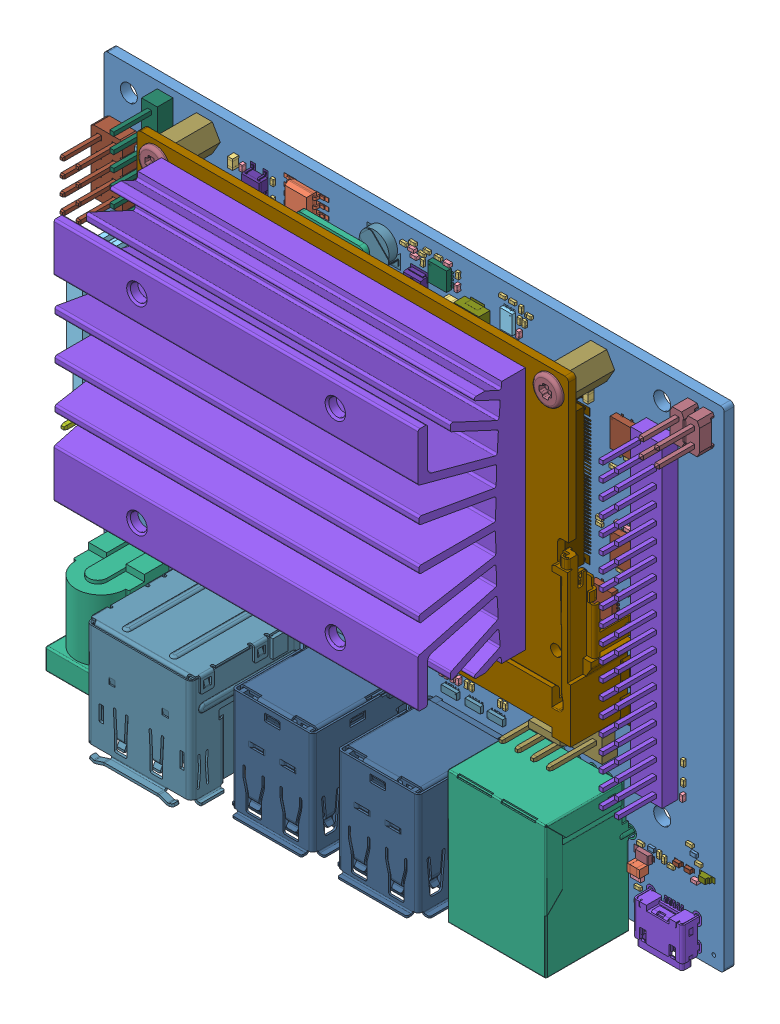
SolidWorks assembly Jetson nano 4GB For New, configuration Default. Lengths in mm.
Overall size (100 81.03 30.51).
388 component instances, 68 part files, 0 mates.
Components (placement in the parent):
- 142-13449-1000-A02_ASM-1: 142-13449-1000-A02_ASM [142-13449-1000-A02_ASM] at origin size (100 81.03 23.18)
  - 142-13449-1000-A02-1: 142-13449-1000-A02 [142-13449-1000-A02] at origin size (100 79 1.57)
  - 315-1109-000_1-1: 315-1109-000_1 [315-1109-000_1] at (5.6 4.9 1.575) x (-1 0 0) z (0 0 1) size (4.5 3.5 0.8)
  - 0402_H040-1: 0402_H040 [0402_H040] at (8 -0.825 1.575) size (1 0.5 0.4)
  - 0402_H060-1: 0402_H060 [0402_H060] at (1 5 1.575) x (0 -1 0) z (0 0 1) size (1 0.5 0.6)
  - 0402_H040-2: 0402_H040 [0402_H040] at (9.9 -0.3 1.575) size (1 0.5 0.4)
  - 0402_H040-3: 0402_H040 [0402_H040] at (8.296 51.194 1.575) x (-1 0 0) z (0 0 1) size (1 0.5 0.4)
  - 0402_H040-4: 0402_H040 [0402_H040] at (76.2 36.9 1.575) x (-1 0 0) z (0 0 1) size (1 0.5 0.4)
  - 0402_H040-5: 0402_H040 [0402_H040] at (37.8 2.87 1.575) x (0 -1 0) z (0 0 1) size (1 0.5 0.4)
  - 0402_H040-6: 0402_H040 [0402_H040] at (38.6 2.87 1.575) x (0 -1 0) z (0 0 1) size (1 0.5 0.4)
  - 0402_H060-2: 0402_H060 [0402_H060] at (14.2 7.7 1.575) x (0 -1 0) z (0 0 1) size (1 0.5 0.6)
  - 0402_H040-7: 0402_H040 [0402_H040] at (64 27.5 1.575) x (-1 0 0) z (0 0 1) size (1 0.5 0.4)
  - 0402_H060-3: 0402_H060 [0402_H060] at (18.6 43.15 1.575) x (-1 0 0) z (0 0 1) size (1 0.5 0.6)
  - 0402_H060-4: 0402_H060 [0402_H060] at (65.5 52.8 1.575) x (0 1 0) z (0 0 1) size (1 0.5 0.6)
  - 0402_H060-5: 0402_H060 [0402_H060] at (64 28.4 1.575) x (-1 0 0) z (0 0 1) size (1 0.5 0.6)
  - 0402_H040-8: 0402_H040 [0402_H040] at (60.95 25.85 1.575) size (1 0.5 0.4)
  - 0402_H060-6: 0402_H060 [0402_H060] at (17.3 7.7 1.575) x (0 -1 0) z (0 0 1) size (1 0.5 0.6)
  - 0402_H060-7: 0402_H060 [0402_H060] at (18.6 7.7 1.575) x (0 -1 0) z (0 0 1) size (1 0.5 0.6)
  - 0402_H060-8: 0402_H060 [0402_H060] at (12.9 7.7 1.575) x (0 -1 0) z (0 0 1) size (1 0.5 0.6)
  - 0402_H060-9: 0402_H060 [0402_H060] at (80.9 37.7 1.575) x (-1 0 0) z (0 0 1) size (1 0.5 0.6)
  - 0402_H040-9: 0402_H040 [0402_H040] at (79.5 31.3 1.575) size (1 0.5 0.4)
  - 0402_H040-10: 0402_H040 [0402_H040] at (81 31.3 1.575) x (-1 0 0) z (0 0 1) size (1 0.5 0.4)
  - 0402_H060-10: 0402_H060 [0402_H060] at (79.3 37.7 1.575) size (1 0.5 0.6)
  - 0402_H060-11: 0402_H060 [0402_H060] at (74.8 4.05 1.575) x (-1 0 0) z (0 0 1) size (1 0.5 0.6)
  - 0402_H040-11: 0402_H040 [0402_H040] at (65.675 6.15 1.575) x (0 -1 0) z (0 0 1) size (1 0.5 0.4)
  - 0402_H060-12: 0402_H060 [0402_H060] at (67.7 6.85 1.575) x (0 1 0) z (0 0 1) size (1 0.5 0.6)
  - 0402_H040-12: 0402_H040 [0402_H040] at (64.475 5.8 1.575) x (-1 0 0) z (0 0 1) size (1 0.5 0.4)
  - 0402_H040-13: 0402_H040 [0402_H040] at (67.725 5.325 1.575) x (0 1 0) z (0 0 1) size (1 0.5 0.4)
  - 0402_H060-13: 0402_H060 [0402_H060] at (46.1 59.45 1.575) size (1 0.5 0.6)
  - 0402_H040-14: 0402_H040 [0402_H040] at (44.65 59.45 1.575) size (1 0.5 0.4)
  - 0402_H040-15: 0402_H040 [0402_H040] at (46.1 60.25 1.575) size (1 0.5 0.4)
  - 0402_H060-14: 0402_H060 [0402_H060] at (53.35 57.7 1.575) x (0 -1 0) z (0 0 1) size (1 0.5 0.6)
  - 0402_H040-16: 0402_H040 [0402_H040] at (47.6 59.45 1.575) size (1 0.5 0.4)
  - 0402_H040-17: 0402_H040 [0402_H040] at (48.4 60.25 1.575) size (1 0.5 0.4)
  - 0402_H040-18: 0402_H040 [0402_H040] at (47.7 58.325 1.575) x (0 1 0) z (0 0 1) size (1 0.5 0.4)
  - 0402_H060-15: 0402_H060 [0402_H060] at (46.5 58.65 1.575) x (-1 0 0) z (0 0 1) size (1 0.5 0.6)
  - 0402_H060-16: 0402_H060 [0402_H060] at (51.8 60.25 1.575) size (1 0.5 0.6)
  - 0402_H040-19: 0402_H040 [0402_H040] at (53.35 59.4 1.575) x (0 -1 0) z (0 0 1) size (1 0.5 0.4)
  - 0402_H040-20: 0402_H040 [0402_H040] at (50.2 60.25 1.575) x (-1 0 0) z (0 0 1) size (1 0.5 0.4)
  - 0402_H060-17: 0402_H060 [0402_H060] at (18.6 43.95 1.575) x (-1 0 0) z (0 0 1) size (1 0.5 0.6)
  - 0402_H060-18: 0402_H060 [0402_H060] at (52.75 2.9 1.575) x (0 -1 0) z (0 0 1) size (1 0.5 0.6)
  - 0402_H060-19: 0402_H060 [0402_H060] at (22.35 47.4 1.575) x (-1 0 0) z (0 0 1) size (1 0.5 0.6)
  - 0402_H060-20: 0402_H060 [0402_H060] at (20.55 47.4 1.575) x (-1 0 0) z (0 0 1) size (1 0.5 0.6)
  - 0402_H060-21: 0402_H060 [0402_H060] at (21.95 34.55 1.575) x (0 -1 0) z (0 0 1) size (1 0.5 0.6)
  - 0402_H060-22: 0402_H060 [0402_H060] at (21.05 34.55 1.575) x (0 -1 0) z (0 0 1) size (1 0.5 0.6)
  - 0402_H060-23: 0402_H060 [0402_H060] at (53.55 2.9 1.575) x (0 -1 0) z (0 0 1) size (1 0.5 0.6)
  - 0402_H060-24: 0402_H060 [0402_H060] at (25.4 54 1.575) x (-1 0 0) z (0 0 1) size (1 0.5 0.6)
  - 0402_H060-25: 0402_H060 [0402_H060] at (24 34.58 1.575) x (0 -1 0) z (0 0 1) size (1 0.5 0.6)
  - 0402_H040-21: 0402_H040 [0402_H040] at (55.6 2.95 1.575) x (0 -1 0) z (0 0 1) size (1 0.5 0.4)
  - 0402_H040-22: 0402_H040 [0402_H040] at (20.13 34.53 1.575) x (0 1 0) z (0 0 1) size (1 0.5 0.4)
  - 0402_H060-26: 0402_H060 [0402_H060] at (18.4 35.15 1.575) x (0 1 0) z (0 0 1) size (1 0.5 0.6)
  - 0402_H060-27: 0402_H060 [0402_H060] at (18.4 36.75 1.575) x (0 1 0) z (0 0 1) size (1 0.5 0.6)
  - 0402_H040-23: 0402_H040 [0402_H040] at (39.6 2.87 1.575) x (0 -1 0) z (0 0 1) size (1 0.5 0.4)
  - 0402_H040-24: 0402_H040 [0402_H040] at (40.4 2.87 1.575) x (0 -1 0) z (0 0 1) size (1 0.5 0.4)
  - 0402_H040-25: 0402_H040 [0402_H040] at (60.95 2.95 1.575) x (0 -1 0) z (0 0 1) size (1 0.5 0.4)
  - 0402_H040-26: 0402_H040 [0402_H040] at (60.15 2.95 1.575) x (0 -1 0) z (0 0 1) size (1 0.5 0.4)
  - 0402_H040-27: 0402_H040 [0402_H040] at (54.8 2.95 1.575) x (0 -1 0) z (0 0 1) size (1 0.5 0.4)
  - 0402_H040-28: 0402_H040 [0402_H040] at (31.6 54 1.575) size (1 0.5 0.4)
  - 0402_H040-29: 0402_H040 [0402_H040] at (27.4 54 1.575) size (1 0.5 0.4)
  - 0402_H040-30: 0402_H040 [0402_H040] at (29.6 54 1.575) x (-1 0 0) z (0 0 1) size (1 0.5 0.4)
  - 0402_H040-31: 0402_H040 [0402_H040] at (63.775 -14.475 1.575) size (1 0.5 0.4)
  - 0402_H040-32: 0402_H040 [0402_H040] at (63.775 -15.275 1.575) size (1 0.5 0.4)
  - 0402_H040-33: 0402_H040 [0402_H040] at (8.025 41.475 1.575) x (-1 0 0) z (0 0 1) size (1 0.5 0.4)
  - 0402_H060-28: 0402_H060 [0402_H060] at (63.95 1.25 1.575) x (0 1 0) z (0 0 1) size (1 0.5 0.6)
  - 0402_H060-29: 0402_H060 [0402_H060] at (2.95 54.05 1.575) x (0 1 0) z (0 0 1) size (1 0.5 0.6)
  - 0402_H040-34: 0402_H040 [0402_H040] at (92.2 -3.45 1.575) x (-1 0 0) z (0 0 1) size (1 0.5 0.4)
  - 0402_H060-30: 0402_H060 [0402_H060] at (32.85 7.7 1.575) x (0 -1 0) z (0 0 1) size (1 0.5 0.6)
  - 0402_H060-31: 0402_H060 [0402_H060] at (27.25 7.7 1.575) x (0 -1 0) z (0 0 1) size (1 0.5 0.6)
  - 0402_H060-32: 0402_H060 [0402_H060] at (31.25 7.7 1.575) x (0 -1 0) z (0 0 1) size (1 0.5 0.6)
  - 0402_H060-33: 0402_H060 [0402_H060] at (28.85 7.7 1.575) x (0 -1 0) z (0 0 1) size (1 0.5 0.6)
  - 0402_H060-34: 0402_H060 [0402_H060] at (32.05 7.7 1.575) x (0 -1 0) z (0 0 1) size (1 0.5 0.6)
  - 0402_H060-35: 0402_H060 [0402_H060] at (28.05 7.7 1.575) x (0 -1 0) z (0 0 1) size (1 0.5 0.6)
  - 0402_H060-36: 0402_H060 [0402_H060] at (30.45 7.7 1.575) x (0 -1 0) z (0 0 1) size (1 0.5 0.6)
  - 0402_H060-37: 0402_H060 [0402_H060] at (29.65 7.7 1.575) x (0 -1 0) z (0 0 1) size (1 0.5 0.6)
  - 0402_H060-38: 0402_H060 [0402_H060] at (24.65 6.41 1.575) x (0 -1 0) z (0 0 1) size (1 0.5 0.6)
  - 0402_H060-39: 0402_H060 [0402_H060] at (25.85 6.41 1.575) x (0 -1 0) z (0 0 1) size (1 0.5 0.6)
  - 0402_H060-40: 0402_H060 [0402_H060] at (4.2 36.5 1.575) x (0 1 0) z (0 0 1) size (1 0.5 0.6)
  - 0402_H060-41: 0402_H060 [0402_H060] at (89.7 4.7 1.575) x (0 -1 0) z (0 0 1) size (1 0.5 0.6)
  - 0402_H060-42: 0402_H060 [0402_H060] at (82.5 3.8 1.575) x (0 -1 0) z (0 0 1) size (1 0.5 0.6)
  - 0402_H060-43: 0402_H060 [0402_H060] at (12.65 49.7 1.575) size (1 0.5 0.6)
  - 0402_H060-44: 0402_H060 [0402_H060] at (11.2 50.15 1.575) x (0 -1 0) z (0 0 1) size (1 0.5 0.6)
  - 0402_H060-45: 0402_H060 [0402_H060] at (26.5 34.55 1.575) x (0 -1 0) z (0 0 1) size (1 0.5 0.6)
  - 0402_H060-46: 0402_H060 [0402_H060] at (29.9 34.5 1.575) x (0 -1 0) z (0 0 1) size (1 0.5 0.6)
  - 0402_H060-47: 0402_H060 [0402_H060] at (31.7 40.15 1.575) x (0 1 0) z (0 0 1) size (1 0.5 0.6)
  - 0402_H060-48: 0402_H060 [0402_H060] at (31.15 42.5 1.575) x (0 1 0) z (0 0 1) size (1 0.5 0.6)
  - 0402_H060-49: 0402_H060 [0402_H060] at (19.2 47.05 1.575) x (0 1 0) z (0 0 1) size (1 0.5 0.6)
  - 0402_H060-50: 0402_H060 [0402_H060] at (17.95 42 1.575) x (0 -1 0) z (0 0 1) size (1 0.5 0.6)
  - 0402_H060-51: 0402_H060 [0402_H060] at (27.3 48.25 1.575) x (0 1 0) z (0 0 1) size (1 0.5 0.6)
  - 0402_H060-52: 0402_H060 [0402_H060] at (31.7 37.85 1.575) x (0 -1 0) z (0 0 1) size (1 0.5 0.6)
  - 0402_H060-53: 0402_H060 [0402_H060] at (29.6 48.35 1.575) x (0 1 0) z (0 0 1) size (1 0.5 0.6)
  - 0402_H060-54: 0402_H060 [0402_H060] at (18.8 38.75 1.575) x (-1 0 0) z (0 0 1) size (1 0.5 0.6)
  - 0402_H060-55: 0402_H060 [0402_H060] at (18.7 57.2 1.575) x (0 -1 0) z (0 0 1) size (1 0.5 0.6)
  - 0402_H060-56: 0402_H060 [0402_H060] at (34.1 2.9 1.575) x (0 -1 0) z (0 0 1) size (1 0.5 0.6)
  - 0402_H060-57: 0402_H060 [0402_H060] at (35.8 2.9 1.575) x (0 -1 0) z (0 0 1) size (1 0.5 0.6)
  - 0402_H060-58: 0402_H060 [0402_H060] at (34.9 2.9 1.575) x (0 -1 0) z (0 0 1) size (1 0.5 0.6)
  - 0402_H060-59: 0402_H060 [0402_H060] at (36.6 2.9 1.575) x (0 -1 0) z (0 0 1) size (1 0.5 0.6)
  - 0402_H060-60: 0402_H060 [0402_H060] at (11.325 44.725 1.575) size (1 0.5 0.6)
  - 0402_H060-61: 0402_H060 [0402_H060] at (50.95 2.9 1.575) x (0 -1 0) z (0 0 1) size (1 0.5 0.6)
  - 0402_H060-62: 0402_H060 [0402_H060] at (51.75 2.9 1.575) x (0 -1 0) z (0 0 1) size (1 0.5 0.6)
  - 0402_H060-63: 0402_H060 [0402_H060] at (11.55 39.7 1.575) size (1 0.5 0.6)
  - 0402_H060-64: 0402_H060 [0402_H060] at (9.5 -8.5 1.575) x (-1 0 0) z (0 0 1) size (1 0.5 0.6)
  - 0402_H060-65: 0402_H060 [0402_H060] at (61.35 38.05 1.575) x (0 -1 0) z (0 0 1) size (1 0.5 0.6)
  - 0402_H060-66: 0402_H060 [0402_H060] at (60.55 38.05 1.575) x (0 -1 0) z (0 0 1) size (1 0.5 0.6)
  - 0402_H060-67: 0402_H060 [0402_H060] at (29.3 25.65 1.575) x (0 -1 0) z (0 0 1) size (1 0.5 0.6)
  - 0402_H060-68: 0402_H060 [0402_H060] at (63.3 56.2 1.575) x (0 1 0) z (0 0 1) size (1 0.5 0.6)
  - 0402_H060-69: 0402_H060 [0402_H060] at (20.5 54.2 1.575) size (1 0.5 0.6)
  - 0402_H060-70: 0402_H060 [0402_H060] at (60.1 32.15 1.575) x (0 1 0) z (0 0 1) size (1 0.5 0.6)
  - 0402_H060-71: 0402_H060 [0402_H060] at (60.9 32.15 1.575) x (0 1 0) z (0 0 1) size (1 0.5 0.6)
  - 0402_H060-72: 0402_H060 [0402_H060] at (18.6 44.85 1.575) size (1 0.5 0.6)
  - 0402_H060-73: 0402_H060 [0402_H060] at (18.6 45.65 1.575) size (1 0.5 0.6)
  - 0402_H060-74: 0402_H060 [0402_H060] at (18.1 27.25 1.575) size (1 0.5 0.6)
  - 0402_H060-75: 0402_H060 [0402_H060] at (15.1 7.7 1.575) x (0 -1 0) z (0 0 1) size (1 0.5 0.6)
  - 0402_H060-76: 0402_H060 [0402_H060] at (16.4 7.7 1.575) x (0 -1 0) z (0 0 1) size (1 0.5 0.6)
  - 0402_H060-77: 0402_H060 [0402_H060] at (20.8 7.7 1.575) x (0 -1 0) z (0 0 1) size (1 0.5 0.6)
  - 0402_H060-78: 0402_H060 [0402_H060] at (19.5 7.7 1.575) x (0 -1 0) z (0 0 1) size (1 0.5 0.6)
  - 0402_H060-79: 0402_H060 [0402_H060] at (21.9 2.8 1.575) size (1 0.5 0.6)
  - 0402_H060-80: 0402_H060 [0402_H060] at (12.75 29 1.575) size (1 0.5 0.6)
  - 0402_H060-81: 0402_H060 [0402_H060] at (10.225 5.1 1.575) size (1 0.5 0.6)
  - 0402_H060-82: 0402_H060 [0402_H060] at (22.8 27.65 1.575) x (0 1 0) z (0 0 1) size (1 0.5 0.6)
  - 0402_H060-83: 0402_H060 [0402_H060] at (18.85 25.15 1.575) x (0 -1 0) z (0 0 1) size (1 0.5 0.6)
  - 0402_H060-84: 0402_H060 [0402_H060] at (17.95 40.1 1.575) x (0 1 0) z (0 0 1) size (1 0.5 0.6)
  - 0402_H040-35: 0402_H040 [0402_H040] at (20.8 6.2 1.575) x (0 1 0) z (0 0 1) size (1 0.5 0.4)
  - 0402_H040-36: 0402_H040 [0402_H040] at (76 22.7 1.575) size (1 0.5 0.4)
  - 0402_H040-37: 0402_H040 [0402_H040] at (23.7 26.85 1.575) x (0 1 0) z (0 0 1) size (1 0.5 0.4)
  - 0402_H040-38: 0402_H040 [0402_H040] at (18 25.15 1.575) x (0 1 0) z (0 0 1) size (1 0.5 0.4)
  - 0402_H040-39: 0402_H040 [0402_H040] at (17.3 28.25 1.575) x (-1 0 0) z (0 0 1) size (1 0.5 0.4)
  - 0402_H040-40: 0402_H040 [0402_H040] at (13.15 4.2 1.575) x (0 -1 0) z (0 0 1) size (1 0.5 0.4)
  - 0402_H040-41: 0402_H040 [0402_H040] at (17.2 30.15 1.575) x (0 -1 0) z (0 0 1) size (1 0.5 0.4)
  - 0402_H040-42: 0402_H040 [0402_H040] at (14.2 6.2 1.575) x (0 1 0) z (0 0 1) size (1 0.5 0.4)
  - 0402_H040-43: 0402_H040 [0402_H040] at (12.9 6.2 1.575) x (0 1 0) z (0 0 1) size (1 0.5 0.4)
  - 0402_H040-44: 0402_H040 [0402_H040] at (15.1 6.2 1.575) x (0 1 0) z (0 0 1) size (1 0.5 0.4)
  - 0402_H040-45: 0402_H040 [0402_H040] at (16.4 6.2 1.575) x (0 1 0) z (0 0 1) size (1 0.5 0.4)
  - 0402_H040-46: 0402_H040 [0402_H040] at (19.5 6.2 1.575) x (0 1 0) z (0 0 1) size (1 0.5 0.4)
  - 0402_H040-47: 0402_H040 [0402_H040] at (17.3 6.2 1.575) x (0 1 0) z (0 0 1) size (1 0.5 0.4)
  - 0402_H040-48: 0402_H040 [0402_H040] at (18.6 6.2 1.575) x (0 1 0) z (0 0 1) size (1 0.5 0.4)
  - 0402_H040-49: 0402_H040 [0402_H040] at (24.2 24.55 1.575) x (0 1 0) z (0 0 1) size (1 0.5 0.4)
  - 0402_H040-50: 0402_H040 [0402_H040] at (23.5 54.9 1.575) x (0 1 0) z (0 0 1) size (1 0.5 0.4)
  - 0402_H040-51: 0402_H040 [0402_H040] at (13.2 39.75 1.575) x (-1 0 0) z (0 0 1) size (1 0.5 0.4)
  - 0402_H040-52: 0402_H040 [0402_H040] at (80.7 47.4 1.575) x (-1 0 0) z (0 0 1) size (1 0.5 0.4)
  - 0402_H040-53: 0402_H040 [0402_H040] at (77.5 22.7 1.575) x (-1 0 0) z (0 0 1) size (1 0.5 0.4)
  - 0402_H040-54: 0402_H040 [0402_H040] at (9.25 -12.75 1.575) x (-1 0 0) z (0 0 1) size (1 0.5 0.4)
  - 0402_H040-55: 0402_H040 [0402_H040] at (9.25 -11.95 1.575) x (-1 0 0) z (0 0 1) size (1 0.5 0.4)
  - 0402_H040-56: 0402_H040 [0402_H040] at (64.475 6.7 1.575) size (1 0.5 0.4)
  - 0402_H040-57: 0402_H040 [0402_H040] at (29.3 24 1.575) x (0 1 0) z (0 0 1) size (1 0.5 0.4)
  - 0402_H040-58: 0402_H040 [0402_H040] at (64.2 32.5 1.575) x (0 1 0) z (0 0 1) size (1 0.5 0.4)
  - 0402_H040-59: 0402_H040 [0402_H040] at (64.15 47.45 1.575) x (0 -1 0) z (0 0 1) size (1 0.5 0.4)
  - 0402_H040-60: 0402_H040 [0402_H040] at (64.2 31 1.575) x (0 -1 0) z (0 0 1) size (1 0.5 0.4)
  - 0402_H040-61: 0402_H040 [0402_H040] at (76.2 36.1 1.575) x (-1 0 0) z (0 0 1) size (1 0.5 0.4)
  - 0402_H040-62: 0402_H040 [0402_H040] at (78.4 45.15 1.575) size (1 0.5 0.4)
  - 0402_H040-63: 0402_H040 [0402_H040] at (81.7 38.6 1.575) size (1 0.5 0.4)
  - 0402_H040-64: 0402_H040 [0402_H040] at (81.7 39.4 1.575) size (1 0.5 0.4)
  - 0402_H040-65: 0402_H040 [0402_H040] at (59.35 51.825 1.575) size (1 0.5 0.4)
  - 0402_H040-66: 0402_H040 [0402_H040] at (60.825 51.825 1.575) x (-1 0 0) z (0 0 1) size (1 0.5 0.4)
  - 0402_H040-67: 0402_H040 [0402_H040] at (89.7 9.5 1.575) x (0 1 0) z (0 0 1) size (1 0.5 0.4)
  - 0402_H040-68: 0402_H040 [0402_H040] at (89.7 6.7 1.575) x (0 1 0) z (0 0 1) size (1 0.5 0.4)
  - 0402_H040-69: 0402_H040 [0402_H040] at (3.9 34.2 1.575) x (0 -1 0) z (0 0 1) size (1 0.5 0.4)
  - 0402_H040-70: 0402_H040 [0402_H040] at (5.1 35 1.575) x (0 1 0) z (0 0 1) size (1 0.5 0.4)
  - 0402_H040-71: 0402_H040 [0402_H040] at (32.85 5.81 1.575) x (0 -1 0) z (0 0 1) size (1 0.5 0.4)
  - 0402_H040-72: 0402_H040 [0402_H040] at (32.05 5.81 1.575) x (0 -1 0) z (0 0 1) size (1 0.5 0.4)
  - 0402_H040-73: 0402_H040 [0402_H040] at (27.25 5.81 1.575) x (0 -1 0) z (0 0 1) size (1 0.5 0.4)
  - 0402_H040-74: 0402_H040 [0402_H040] at (28.05 5.81 1.575) x (0 -1 0) z (0 0 1) size (1 0.5 0.4)
  - 0402_H040-75: 0402_H040 [0402_H040] at (31.25 5.81 1.575) x (0 -1 0) z (0 0 1) size (1 0.5 0.4)
  - 0402_H040-76: 0402_H040 [0402_H040] at (30.45 5.81 1.575) x (0 -1 0) z (0 0 1) size (1 0.5 0.4)
  - 0402_H040-77: 0402_H040 [0402_H040] at (28.85 5.81 1.575) x (0 -1 0) z (0 0 1) size (1 0.5 0.4)
  - 0402_H040-78: 0402_H040 [0402_H040] at (29.65 5.81 1.575) x (0 -1 0) z (0 0 1) size (1 0.5 0.4)
  - 0402_H040-79: 0402_H040 [0402_H040] at (13.5 52.9 1.575) x (-1 0 0) z (0 0 1) size (1 0.5 0.4)
  - 0402_H040-80: 0402_H040 [0402_H040] at (22.35 4 1.575) x (0 -1 0) z (0 0 1) size (1 0.5 0.4)
  - 0402_H040-81: 0402_H040 [0402_H040] at (21.55 4 1.575) x (0 1 0) z (0 0 1) size (1 0.5 0.4)
  - 0402_H040-82: 0402_H040 [0402_H040] at (25.85 4.9 1.575) x (0 -1 0) z (0 0 1) size (1 0.5 0.4)
  - 0402_H040-83: 0402_H040 [0402_H040] at (11.8 52.9 1.575) size (1 0.5 0.4)
  - 0402_H040-84: 0402_H040 [0402_H040] at (9.432 51.594 1.575) x (0 -1 0) z (0 0 1) size (1 0.5 0.4)
  - 0402_H040-85: 0402_H040 [0402_H040] at (8.975 50.3 1.575) size (1 0.5 0.4)
  - 0402_H040-86: 0402_H040 [0402_H040] at (82.8 -5.3 1.575) x (-1 0 0) z (0 0 1) size (1 0.5 0.4)
  - 0402_H040-87: 0402_H040 [0402_H040] at (82.4 -11.6 1.575) x (-1 0 0) z (0 0 1) size (1 0.5 0.4)
  - 0402_H040-88: 0402_H040 [0402_H040] at (22.8 26.05 1.575) x (0 1 0) z (0 0 1) size (1 0.5 0.4)
  - 0402_H040-89: 0402_H040 [0402_H040] at (20.8 28.25 1.575) size (1 0.5 0.4)
  - 0402_H040-90: 0402_H040 [0402_H040] at (20.8 24.65 1.575) x (-1 0 0) z (0 0 1) size (1 0.5 0.4)
  - 0402_H040-91: 0402_H040 [0402_H040] at (18.1 26.45 1.575) size (1 0.5 0.4)
  - 0402_H040-92: 0402_H040 [0402_H040] at (24.65 8.41 1.575) x (0 1 0) z (0 0 1) size (1 0.5 0.4)
  - 0402_H040-93: 0402_H040 [0402_H040] at (25.85 8.41 1.575) x (0 1 0) z (0 0 1) size (1 0.5 0.4)
  - 0402_H040-94: 0402_H040 [0402_H040] at (3.8 54.4 1.575) x (0 -1 0) z (0 0 1) size (1 0.5 0.4)
  - 0402_H040-95: 0402_H040 [0402_H040] at (2.45 44.45 1.575) x (0 -1 0) z (0 0 1) size (1 0.5 0.4)
  - 0402_H040-96: 0402_H040 [0402_H040] at (24.65 4.9 1.575) x (0 1 0) z (0 0 1) size (1 0.5 0.4)
  - 0402_H040-97: 0402_H040 [0402_H040] at (22.15 7.6 1.575) x (-1 0 0) z (0 0 1) size (1 0.5 0.4)
  - 0402_H040-98: 0402_H040 [0402_H040] at (79.2 47.4 1.575) size (1 0.5 0.4)
  - 0402_H040-99: 0402_H040 [0402_H040] at (19 28.25 1.575) size (1 0.5 0.4)
  - 0402_H040-100: 0402_H040 [0402_H040] at (9.65 9.7 1.575) x (0 -1 0) z (0 0 1) size (1 0.5 0.4)
  - 0402_H040-101: 0402_H040 [0402_H040] at (28.35 34.45 1.575) x (0 1 0) z (0 0 1) size (1 0.5 0.4)
  - 0402_H040-102: 0402_H040 [0402_H040] at (25.2 34.55 1.575) x (0 1 0) z (0 0 1) size (1 0.5 0.4)
  - 0402_H040-103: 0402_H040 [0402_H040] at (10.625 6.35 1.575) x (0 -1 0) z (0 0 1) size (1 0.5 0.4)
  - 0402_H040-104: 0402_H040 [0402_H040] at (9.825 6.35 1.575) x (0 1 0) z (0 0 1) size (1 0.5 0.4)
  - 0402_H040-105: 0402_H040 [0402_H040] at (4.775 42.975 1.575) x (0 1 0) z (0 0 1) size (1 0.5 0.4)
  - 0402_H040-106: 0402_H040 [0402_H040] at (19.8 32.9 1.575) x (-1 0 0) z (0 0 1) size (1 0.5 0.4)
  - 0402_H040-107: 0402_H040 [0402_H040] at (22.35 24.65 1.575) x (-1 0 0) z (0 0 1) size (1 0.5 0.4)
  - 0402_H040-108: 0402_H040 [0402_H040] at (62.4 54.7 1.575) size (1 0.5 0.4)
  - 0402_H040-109: 0402_H040 [0402_H040] at (62.2 60.05 1.575) x (-1 0 0) z (0 0 1) size (1 0.5 0.4)
  - 0402_H040-110: 0402_H040 [0402_H040] at (23.5 57.5 1.575) x (0 1 0) z (0 0 1) size (1 0.5 0.4)
  - 0402_H040-111: 0402_H040 [0402_H040] at (12.8 44.725 1.575) size (1 0.5 0.4)
  - 0402_H040-112: 0402_H040 [0402_H040] at (21.8 31.45 1.575) x (0 1 0) z (0 0 1) size (1 0.5 0.4)
  - 0402_H040-113: 0402_H040 [0402_H040] at (19.25 34.55 1.575) x (0 1 0) z (0 0 1) size (1 0.5 0.4)
  - 0402_H040-114: 0402_H040 [0402_H040] at (0.95 41.55 1.575) size (1 0.5 0.4)
  - 0402_H040-115: 0402_H040 [0402_H040] at (64.1 58 1.575) x (0 1 0) z (0 0 1) size (1 0.5 0.4)
  - 0402_H040-116: 0402_H040 [0402_H040] at (63.3 58 1.575) x (0 -1 0) z (0 0 1) size (1 0.5 0.4)
  - 0402_H040-117: 0402_H040 [0402_H040] at (63.55 59.7 1.575) x (0 -1 0) z (0 0 1) size (1 0.5 0.4)
  - 0402_H060-85: 0402_H060 [0402_H060] at (71.175 4 1.575) x (-1 0 0) z (0 0 1) size (1 0.5 0.6)
  - 0402_H040-118: 0402_H040 [0402_H040] at (86.6 -5.6 1.575) x (0 1 0) z (0 0 1) size (1 0.5 0.4)
  - 0402_H040-119: 0402_H040 [0402_H040] at (85.8 -5.3 1.575) x (0 1 0) z (0 0 1) size (1 0.5 0.4)
  - 0402_H040-120: 0402_H040 [0402_H040] at (10.25 51.6 1.575) x (0 1 0) z (0 0 1) size (1 0.5 0.4)
  - 0402_H040-121: 0402_H040 [0402_H040] at (80.5 28.55 1.575) size (1 0.5 0.4)
  - 0402_H040-122: 0402_H040 [0402_H040] at (13.95 4.2 1.575) x (0 -1 0) z (0 0 1) size (1 0.5 0.4)
  - 0402_H040-123: 0402_H040 [0402_H040] at (15.35 4.2 1.575) x (0 -1 0) z (0 0 1) size (1 0.5 0.4)
  - 0402_H040-124: 0402_H040 [0402_H040] at (16.15 4.2 1.575) x (0 -1 0) z (0 0 1) size (1 0.5 0.4)
  - 0402_H040-125: 0402_H040 [0402_H040] at (20.55 4.2 1.575) x (0 -1 0) z (0 0 1) size (1 0.5 0.4)
  - 0402_H040-126: 0402_H040 [0402_H040] at (19.75 4.2 1.575) x (0 -1 0) z (0 0 1) size (1 0.5 0.4)
  - 0402_H040-127: 0402_H040 [0402_H040] at (17.6 4.2 1.575) x (0 -1 0) z (0 0 1) size (1 0.5 0.4)
  - 0402_H040-128: 0402_H040 [0402_H040] at (18.4 4.2 1.575) x (0 -1 0) z (0 0 1) size (1 0.5 0.4)
  - 0402_H060-86: 0402_H060 [0402_H060] at (64.25 -13.325 1.575) x (0 -1 0) z (0 0 1) size (1 0.5 0.6)
  - 0402_H060-87: 0402_H060 [0402_H060] at (64.225 -11.825 1.575) x (0 1 0) z (0 0 1) size (1 0.5 0.6)
  - 0402_H040-129: 0402_H040 [0402_H040] at (63.8 -6.85 1.575) x (0 1 0) z (0 0 1) size (1 0.5 0.4)
  - 0402_H040-130: 0402_H040 [0402_H040] at (81.7 41.95 1.575) size (1 0.5 0.4)
  - 0402_H040-131: 0402_H040 [0402_H040] at (87.75 -6 1.575) x (-1 0 0) z (0 0 1) size (1 0.5 0.4)
  - 0402_H040-132: 0402_H040 [0402_H040] at (82.4 -13.6 1.575) x (-1 0 0) z (0 0 1) size (1 0.5 0.4)
  - 0402_H060-88: 0402_H060 [0402_H060] at (91.75 -5.95 1.575) size (1 0.5 0.6)
  - 0402_H040-133: 0402_H040 [0402_H040] at (3.65 49.25 1.575) x (0 -1 0) z (0 0 1) size (1 0.5 0.4)
  - 0402_H040-134: 0402_H040 [0402_H040] at (2.45 49.25 1.575) x (0 1 0) z (0 0 1) size (1 0.5 0.4)
  - 0402_H040-135: 0402_H040 [0402_H040] at (90.75 -1.45 1.575) x (-1 0 0) z (0 0 1) size (1 0.5 0.4)
  - 0402_H040-136: 0402_H040 [0402_H040] at (8.45 39.55 1.575) x (0 -1 0) z (0 0 1) size (1 0.5 0.4)
  - 0402_H060-89: 0402_H060 [0402_H060] at (8.85 -5.25 1.575) x (-1 0 0) z (0 0 1) size (1 0.5 0.6)
  - 0402_H040-137: 0402_H040 [0402_H040] at (18.6 32.55 1.575) x (0 1 0) z (0 0 1) size (1 0.5 0.4)
  - 0402_H060-90: 0402_H060 [0402_H060] at (4.5 44.45 1.575) x (0 1 0) z (0 0 1) size (1 0.5 0.6)
  - 0402_H040-138: 0402_H040 [0402_H040] at (8.35 2.75 1.575) size (1 0.5 0.4)
  - 0402_H040-139: 0402_H040 [0402_H040] at (9.4 1.95 1.575) size (1 0.5 0.4)
  - 0402_H040-140: 0402_H040 [0402_H040] at (8.2 1.55 1.575) x (0 1 0) z (0 0 1) size (1 0.5 0.4)
  - 0402_H060-91: 0402_H060 [0402_H060] at (8.5 3.875 1.575) x (0 -1 0) z (0 0 1) size (1 0.5 0.6)
  - 0402_H060-92: 0402_H060 [0402_H060] at (-0.8 41.5 1.575) x (-1 0 0) z (0 0 1) size (1 0.5 0.6)
  - 0402_H040-141: 0402_H040 [0402_H040] at (-1.35 7.75 1.575) size (1 0.5 0.4)
  - 0402_H040-142: 0402_H040 [0402_H040] at (8 0.425 1.575) size (1 0.5 0.4)
  - 0402_H040-143: 0402_H040 [0402_H040] at (67.9 4.025 1.575) x (-1 0 0) z (0 0 1) size (1 0.5 0.4)
  - 0402_H040-144: 0402_H040 [0402_H040] at (60.6 60.05 1.575) x (-1 0 0) z (0 0 1) size (1 0.5 0.4)
  - 0402_H040-145: 0402_H040 [0402_H040] at (72.85 4 1.575) x (-1 0 0) z (0 0 1) size (1 0.5 0.4)
  - 0402_H040-146: 0402_H040 [0402_H040] at (64.8 59.35 1.575) size (1 0.5 0.4)
  - 0402_H040-147: 0402_H040 [0402_H040] at (7.2 7.3 1.575) size (1 0.5 0.4)
  - 0402_H040-148: 0402_H040 [0402_H040] at (8.5 5.35 1.575) x (0 1 0) z (0 0 1) size (1 0.5 0.4)
  - 0402_H040-149: 0402_H040 [0402_H040] at (8.475 7.075 1.575) x (0 1 0) z (0 0 1) size (1 0.5 0.4)
  - VIRTUAL_SHORT-1: VIRTUAL_SHORT [VIRTUAL_SHORT] at (23.5 32.9 1.575) x (0 1 0) z (0 0 1) size (0.25 0.25 1)
  - VIRTUAL_SHORT-2: VIRTUAL_SHORT [VIRTUAL_SHORT] at (26.85 32.85 1.575) x (0 1 0) z (0 0 1) size (0.25 0.25 1)
  - VIRTUAL_SHORT-3: VIRTUAL_SHORT [VIRTUAL_SHORT] at (30.6 33.8 1.575) x (0 1 0) z (0 0 1) size (0.25 0.25 1)
  - VIRTUAL_SHORT-4: VIRTUAL_SHORT [VIRTUAL_SHORT] at (32.65 39.75 1.575) x (-1 0 0) z (0 0 1) size (0.25 0.25 1)
  - VIRTUAL_SHORT-5: VIRTUAL_SHORT [VIRTUAL_SHORT] at (31.85 42.1 1.575) x (-1 0 0) z (0 0 1) size (0.25 0.25 1)
  - VIRTUAL_SHORT-6: VIRTUAL_SHORT [VIRTUAL_SHORT] at (17.35 42.4 1.575) size (0.25 0.25 1)
  - VIRTUAL_SHORT-7: VIRTUAL_SHORT [VIRTUAL_SHORT] at (18.6 46.6 1.575) size (0.25 0.25 1)
  - VIRTUAL_SHORT-8: VIRTUAL_SHORT [VIRTUAL_SHORT] at (20.9 32.9 1.575) x (0 1 0) z (0 0 1) size (0.25 0.25 1)
  - VIRTUAL_SHORT-9: VIRTUAL_SHORT [VIRTUAL_SHORT] at (28.6 48.25 1.575) x (0 -1 0) z (0 0 1) size (0.25 0.25 1)
  - VIRTUAL_SHORT-10: VIRTUAL_SHORT [VIRTUAL_SHORT] at (27.1 49.35 1.575) x (0 -1 0) z (0 0 1) size (0.25 0.25 1)
  - VIRTUAL_SHORT-11: VIRTUAL_SHORT [VIRTUAL_SHORT] at (22.1 32.95 1.575) x (-1 0 0) z (0 0 1) size (0.25 0.25 1)
  - VIRTUAL_SHORT-12: VIRTUAL_SHORT [VIRTUAL_SHORT] at (32.65 38.25 1.575) x (-1 0 0) z (0 0 1) size (0.25 0.25 1)
  - VIRTUAL_SHORT-13: VIRTUAL_SHORT [VIRTUAL_SHORT] at (30.3 48 1.575) x (-1 0 0) z (0 0 1) size (0.25 0.25 1)
  - VIRTUAL_SHORT-14: VIRTUAL_SHORT [VIRTUAL_SHORT] at (17.15 38.95 1.575) size (0.25 0.25 1)
  - VIRTUAL_SHORT-15: VIRTUAL_SHORT [VIRTUAL_SHORT] at (17.15 39.7 1.575) size (0.25 0.25 1)
  - VIRTUAL_SHORT-16: VIRTUAL_SHORT [VIRTUAL_SHORT] at (76.175 4.1 1.575) x (-1 0 0) z (0 0 1) size (0.25 0.25 1)
  - 064-0377-000_2-1: 064-0377-000_2 [064-0377-000_2] at (2 -4.75 1.575) x (0 -1 0) z (0 0 1) size (14.63 10.08 14.5)
  - 074-0117-000_2-1: 074-0117-000_2 [074-0117-000_2] at (0.254 14.3 1.575) size (5.08 2.54 11.66)
  - 090-0096-000_1-1: 090-0096-000_1 [090-0096-000_1] at (3.45 44.4 1.575) x (0 -1 0) z (0 0 1) size (1.2 0.6 0.4)
  - 090-0309-000_1-1: 090-0309-000_1 [090-0309-000_1] at (-1.65 8.7 1.575) x (-1 0 0) z (0 0 1) size (1.2 0.6 0.4)
  - 115-1232-000_2-1: 115-1232-000_2 [115-1232-000_2] at (1.25 6.5 1.575) x (-1 0 0) z (0 0 1) size (0.9 0.9 0.33)
  - 074-0102-000_4-1: 074-0102-000_4 [074-0102-000_4] at (0.254 44.36 1.575) x (0 1 0) z (0 0 1) size (10.16 5.08 11.6)
  - 064-0400-000_1-1: 064-0400-000_1 [064-0400-000_1] at (73.75 7.77 1.575) size (10.16 5.8 13.5)
  - MEC_STANDOFF_PTH_620C380P-1: MEC_STANDOFF_PTH_620C380P [MEC_STANDOFF_PTH_620C380P] at (40.276 40.3 1.575) x (0 1 0) z (0 0 1) size (6.2 6.2 0.73)
  - 090-0231-000_1-1: 090-0231-000_1 [090-0231-000_1] at (35.3 0.7 1.575) x (-1 0 0) z (0 0 1) size (2.5 1.55 0.55)
  - 090-0231-000_1-2: 090-0231-000_1 [090-0231-000_1] at (52.25 0.7 1.575) x (-1 0 0) z (0 0 1) size (2.5 1.55 0.55)
  - 090-0231-000_1-3: 090-0231-000_1 [090-0231-000_1] at (56.05 0.7 1.575) size (2.5 1.55 0.55)
  - 090-0231-000_1-4: 090-0231-000_1 [090-0231-000_1] at (59.65 0.7 1.575) size (2.5 1.55 0.55)
  - 090-0231-000_1-5: 090-0231-000_1 [090-0231-000_1] at (39.1 0.7 1.575) size (2.5 1.55 0.55)
  - 090-0231-000_1-6: 090-0231-000_1 [090-0231-000_1] at (43.1 0.7 1.575) size (2.5 1.55 0.55)
  - 090-0231-000_1-7: 090-0231-000_1 [090-0231-000_1] at (14.6 1.8 1.575) size (2.5 1.55 0.55)
  - 090-0231-000_1-8: 090-0231-000_1 [090-0231-000_1] at (19.1 1.8 1.575) size (2.5 1.55 0.55)
  - 090-0231-000_1-9: 090-0231-000_1 [090-0231-000_1] at (22.5 1.4 1.575) size (2.5 1.55 0.55)
  - 090-0231-000_1-10: 090-0231-000_1 [090-0231-000_1] at (28.45 3.35 1.575) size (2.5 1.55 0.55)
  - 090-0231-000_1-11: 090-0231-000_1 [090-0231-000_1] at (31.65 3.35 1.575) size (2.5 1.55 0.55)
  - 074-0223-000_2-1: 074-0223-000_2 [074-0223-000_2] at (5.85 53.25 1.575) x (0 1 0) z (0 0 1) size (15.24 2.54 11.6)
  - 131-0832-000_2-1: 131-0832-000_2 [131-0832-000_2] at (56.3 54.7 1.575) x (0 -1 0) z (0 0 1) size (4.96 4.06 1.8)
  - 115-0836-000_1-1: 115-0836-000_1 [115-0836-000_1] at (21.1 56.6 1.575) size (2.9 3.58 1.45)
  - 115-0836-000_1-2: 115-0836-000_1 [115-0836-000_1] at (11.8 42.3 1.575) size (2.9 3.58 1.45)
  - 315-0620-000_1-1: 315-0620-000_1 [315-0620-000_1] at (72.1 53.4 1.575) x (0 -1 0) z (0 0 1) size (2.9 3.58 1.1)
  - 315-1062-000_1-1: 315-1062-000_1 [315-1062-000_1] at (26.8 25.15 1.575) x (0 -1 0) z (0 0 1) size (2.9 3.58 1.45)
  - 170-0285-000_1-1: 170-0285-000_1 [170-0285-000_1] at (28.72 57.28 1.575) x (0 1 0) z (0 0 1) size (4.9 7.21 1.75)
  - 115-0138-000_1-1: 115-0138-000_1 [115-0138-000_1] at (9.15 48.55 1.575) x (0 1 0) z (0 0 1) size (2 2.88 1.1)
  - 115-1821-000_1-1: 115-1821-000_1 [115-1821-000_1] at (3.3 40.8 1.575) x (-1 0 0) z (0 0 1) size (2 2.88 1.1)
  - 115-1821-000_1-2: 115-1821-000_1 [115-1821-000_1] at (6.25 39.55 1.575) x (0 -1 0) z (0 0 1) size (2 2.88 1.1)
  - 115-0742-000_2-1: 115-0742-000_2 [115-0742-000_2] at (3.05 46.85 1.575) size (2 2.88 1.1)
  - 115-0742-000_2-2: 115-0742-000_2 [115-0742-000_2] at (3.05 51.65 1.575) x (-1 0 0) z (0 0 1) size (2 2.88 1.1)
  - 115-1821-000_1-3: 115-1821-000_1 [115-1821-000_1] at (59.6 27.6 1.575) x (0 1 0) z (0 0 1) size (2 2.88 1.1)
  - 091-0022-000_1-1: 091-0022-000_1 [091-0022-000_1] at (-0.95 5.7 1.575) size (2 2.51 1.1)
  - 091-0023-000_1-1: 091-0023-000_1 [091-0023-000_1] at (15.25 29.9 1.575) x (0 -1 0) z (0 0 1) size (2 2.51 1.1)
  - 080-1368-000_1-1: 080-1368-000_1 [080-1368-000_1] at (88 -14.3 1.575) size (10.99 7.28 4.95)
  - 080-1656-000_3-1: 080-1656-000_3 [080-1656-000_3] at (44 16.6 1.575) x (-1 0 0) z (0 0 1) size (77.5 25.85 9.76)
  - 090-0243-000_1-1: 090-0243-000_1 [090-0243-000_1] at (8.5 -4.1 1.575) x (-1 0 0) z (0 0 1) size (1.41 0.61 0.45)
  - 090-0243-000_1-2: 090-0243-000_1 [090-0243-000_1] at (9.95 -3.7 1.575) x (0 1 0) z (0 0 1) size (1.41 0.61 0.45)
  - 090-0243-000_1-3: 090-0243-000_1 [090-0243-000_1] at (9.5 -10.95 1.575) x (-1 0 0) z (0 0 1) size (1.41 0.61 0.45)
  - 090-0243-000_1-4: 090-0243-000_1 [090-0243-000_1] at (9.8 -6.25 1.575) x (-1 0 0) z (0 0 1) size (1.41 0.61 0.45)
  - 090-0243-000_1-5: 090-0243-000_1 [090-0243-000_1] at (9.5 -9.5 1.575) x (-1 0 0) z (0 0 1) size (1.41 0.61 0.45)
  - 090-0172-000_1-1: 090-0172-000_1 [090-0172-000_1] at (90.6 -5 1.575) size (1.41 0.61 0.55)
  - 090-0172-000_1-2: 090-0172-000_1 [090-0172-000_1] at (88.8 -5 1.575) x (-1 0 0) z (0 0 1) size (1.41 0.61 0.55)
  - 115-2177-000_2-1: 115-2177-000_2 [115-2177-000_2] at (12.7 51.35 1.575) x (0 1 0) z (0 0 1) size (1.8 1.71 0.4)
  - 090-0233-000_1-1: 090-0233-000_1 [090-0233-000_1] at (83.5 -6.6 1.575) size (3.3 1.3 0.74)
  - 064-0374-000_2-1: 064-0374-000_2 [064-0374-000_2] at (19.75 -9.65 1.575) size (18.1 18.55 21.85)
  - 115-2628-000_3-1: 115-2628-000_3 [115-2628-000_3] at (25.2 41.2 1.575) size (9.5 9.5 0.9)
  - 092-0073-000_1-1: 092-0073-000_1 [092-0073-000_1] at (93.35 -4.75 1.575) x (-1 0 0) z (0 0 1) size (2.46 0.81 0.9)
  - IND_SMD_0402_H060-1: IND_SMD_0402_H060 [IND_SMD_0402_H060] at (12.85 29.9 1.575) x (-1 0 0) z (0 0 1) size (1 0.5 0.6)
  - 1206_H190-1: 1206_H190 [1206_H190] at (82 18.8 1.575) x (0 1 0) z (0 0 1) size (3.2 1.6 1.9)
  - 1206_H190-2: 1206_H190 [1206_H190] at (81.95 13.5 1.575) x (0 -1 0) z (0 0 1) size (3.2 1.6 1.9)
  - 300-0868-000_3-1: 300-0868-000_3 [300-0868-000_3] at (69.6 4 1.575) x (-1 0 0) z (0 0 1) size (1 0.6 0.4)
  - 300-0868-000_3-2: 300-0868-000_3 [300-0868-000_3] at (9.55 0.95 1.575) size (1 0.6 0.4)
  - 300-0868-000_3-3: 300-0868-000_3 [300-0868-000_3] at (19.6 31.45 1.575) x (0 -1 0) z (0 0 1) size (1 0.6 0.4)
  - 300-0868-000_3-4: 300-0868-000_3 [300-0868-000_3] at (91.45 -2.45 1.575) x (-1 0 0) z (0 0 1) size (1 0.6 0.4)
  - 300-0868-000_3-5: 300-0868-000_3 [300-0868-000_3] at (84.6 -5.1 1.575) size (1 0.6 0.4)
  - 300-0868-000_3-6: 300-0868-000_3 [300-0868-000_3] at (66.725 5.875 1.575) x (0 -1 0) z (0 0 1) size (1 0.6 0.4)
  - 300-0868-000_3-7: 300-0868-000_3 [300-0868-000_3] at (20.8 31.45 1.575) x (0 -1 0) z (0 0 1) size (1 0.6 0.4)
  - 300-0868-000_3-8: 300-0868-000_3 [300-0868-000_3] at (62.9 31.35 1.575) x (-1 0 0) z (0 0 1) size (1 0.6 0.4)
  - 300-0868-000_3-9: 300-0868-000_3 [300-0868-000_3] at (65.475 4.8 1.575) x (-1 0 0) z (0 0 1) size (1 0.6 0.4)
  - 300-0868-000_3-10: 300-0868-000_3 [300-0868-000_3] at (63.9 33.85 1.575) x (-1 0 0) z (0 0 1) size (1 0.6 0.4)
  - 300-0868-000_3-11: 300-0868-000_3 [300-0868-000_3] at (15.65 27.9 1.575) size (1 0.6 0.4)
  - 300-0868-000_3-12: 300-0868-000_3 [300-0868-000_3] at (11.8 6.1 1.575) x (0 1 0) z (0 0 1) size (1 0.6 0.4)
  - 300-0868-000_3-13: 300-0868-000_3 [300-0868-000_3] at (22.1 6.25 1.575) x (0 1 0) z (0 0 1) size (1 0.6 0.4)
  - 300-0869-000_3-1: 300-0869-000_3 [300-0869-000_3] at (9.65 8.1 1.575) x (0 -1 0) z (0 0 1) size (1 0.6 0.53)
  - 300-0402-000_1-1: 300-0402-000_1 [300-0402-000_1] at (20.8 26.45 1.575) x (0 -1 0) z (0 0 1) size (2 2.69 1.1)
  - 300-0560-000_1-1: 300-0560-000_1 [300-0560-000_1] at (6.8 43.65 1.575) x (-1 0 0) z (0 0 1) size (2 2.69 1.1)
  - 174-0159-000_2-1: 174-0159-000_2 [174-0159-000_2] at (61.49 57.15 1.575) x (-1 0 0) z (0 0 1) size (2 3.52 0.6)
  - 064-0373-000_2-1: 064-0373-000_2 [064-0373-000_2] at (72.95 -7.825 1.575) size (17.8 21.6 17.45)
  - 064-0375-000_2-1: 064-0375-000_2 [064-0375-000_2] at (19.751 -12.275 1.575) size (16.2 5.58 0.01)
  - 074-0221-000_3-1: 074-0221-000_3 [074-0221-000_3] at (86 29 1.575) x (0 1 0) z (0 0 1) size (50.8 5.08 11.6)
  - 2016MM_H100-1: 2016MM_H100 [2016MM_H100] at (24.5 49.25 1.575) x (0 1 0) z (0 0 1) size (2 1.6 1)
  - 065-0656-000_2-1: 065-0656-000_2 [065-0656-000_2] at (55.6 -10.04 1.575) x (-1 0 0) z (0 0 1) size (16.19 17.45 19.62)
  - 065-0656-000_2-2: 065-0656-000_2 [065-0656-000_2] at (38.6 -10.04 1.575) x (-1 0 0) z (0 0 1) size (16.19 17.45 19.62)
  - 115-1921-000_3-1: 115-1921-000_3 [115-1921-000_3] at (80.45 50.52 1.575) x (0 -1 0) z (0 0 1) size (5 4 1)
  - 115-1921-000_3-2: 115-1921-000_3 [115-1921-000_3] at (80.4 34.5 1.575) x (0 -1 0) z (0 0 1) size (5 4 1)
  - 115-1921-000_3-3: 115-1921-000_3 [115-1921-000_3] at (77.2 25.9 1.575) x (0 -1 0) z (0 0 1) size (5 4 1)
  - 085-0328-000_2-1: 085-0328-000_2 [085-0328-000_2] at (16.28 36.32 1.575) x (0 -1 0) z (0 0 1) size (3.81 2.5 0.6)
  - 074-0216-000_2-1: 074-0216-000_2 [074-0216-000_2] at (92.14 58 1.575) x (-1 0 0) z (0 0 1) size (4.83 5 11.5)
  - 060-0002-000_1-1: 060-0002-000_1 [060-0002-000_1] at (41.2 57.9 1.575) x (0 -1 0) z (0 0 1) size (5.1 5.4 1.68)
  - 316-0697-000_1-1: 316-0697-000_1 [316-0697-000_1] at (50.6 58.1 1.575) x (0 -1 0) z (0 0 1) size (3 3.72 0.8)
  - 032-0256-000_1-1: 032-0256-000_1 [032-0256-000_1] at (5.925 9.425 1.575) size (4.22 2.82 2)
  - 041-0092-000_1-1: 041-0092-000_1 [041-0092-000_1] at (46.9 54.9 1.575) x (0 -1 0) z (0 0 1) size (4.22 2.82 1.2)
  - 080-1243-000_3-1: 080-1243-000_3 [080-1243-000_3] at (69.9 40.3 1.575) x (0 -1 0) z (0 0 1) size (21.9 9.1 4.8)
  - 0805_H140-1: 0805_H140 [0805_H140] at (8.1 -2.1 1.575) size (2.01 1.25 1.4)
  - 0805_H150-1: 0805_H150 [0805_H150] at (82.9 -8.4 1.575) x (-1 0 0) z (0 0 1) size (2.01 1.25 1.5)
  - 0603_H100-1: 0603_H100 [0603_H100] at (6.1 41.525 1.575) x (-1 0 0) z (0 0 1) size (1.6 0.81 1)
  - 0603_H060-1: 0603_H060 [0603_H060] at (63.25 -12 1.575) x (0 1 0) z (0 0 1) size (1.6 0.81 0.6)
  - 0603_H060-2: 0603_H060 [0603_H060] at (63.8 -0.7 1.575) x (0 -1 0) z (0 0 1) size (1.6 0.81 0.6)
  - 0603_H060-3: 0603_H060 [0603_H060] at (82.4 -10 1.575) x (-1 0 0) z (0 0 1) size (1.6 0.81 0.6)
  - 0603_H100-2: 0603_H100 [0603_H100] at (9.486 -7.5 1.575) x (-1 0 0) z (0 0 1) size (1.6 0.81 1)
  - 0603_H100-3: 0603_H100 [0603_H100] at (17.4 57.4 1.575) x (0 -1 0) z (0 0 1) size (1.6 0.81 1)
  - 0603_H100-4: 0603_H100 [0603_H100] at (30.35 25.9 1.575) x (0 -1 0) z (0 0 1) size (1.6 0.81 1)
  - 0603_H100-5: 0603_H100 [0603_H100] at (11.4 45.7 1.575) size (1.6 0.81 1)
  - 0603_H100-6: 0603_H100 [0603_H100] at (3.2 43 1.575) size (1.6 0.81 1)
  - 0603_H100-7: 0603_H100 [0603_H100] at (74.7 53.4 1.575) x (0 -1 0) z (0 0 1) size (1.6 0.81 1)
  - 0603_H100-8: 0603_H100 [0603_H100] at (69.5 53.9 1.575) x (0 -1 0) z (0 0 1) size (1.6 0.81 1)
  - 0603_H100-9: 0603_H100 [0603_H100] at (52.5 52.9 1.575) x (-1 0 0) z (0 0 1) size (1.6 0.81 1)
  - 0603_H100-10: 0603_H100 [0603_H100] at (52.5 54.2 1.575) x (-1 0 0) z (0 0 1) size (1.6 0.81 1)
  - 0603_H100-11: 0603_H100 [0603_H100] at (27.3 51.35 1.575) size (1.6 0.81 1)
  - 0603_H100-12: 0603_H100 [0603_H100] at (22.7 49.1 1.575) x (0 1 0) z (0 0 1) size (1.6 0.81 1)
  - 0603_H100-13: 0603_H100 [0603_H100] at (26.2 48.8 1.575) x (0 1 0) z (0 0 1) size (1.6 0.81 1)
  - 0603_H100-14: 0603_H100 [0603_H100] at (20.9 49.1 1.575) x (0 1 0) z (0 0 1) size (1.6 0.81 1)
  - 0603_H100-15: 0603_H100 [0603_H100] at (65.5 27.4 1.575) x (0 -1 0) z (0 0 1) size (1.6 0.81 1)
  - 0603_H100-16: 0603_H100 [0603_H100] at (63.8 52.2 1.575) x (-1 0 0) z (0 0 1) size (1.6 0.81 1)
  - 0603_H100-17: 0603_H100 [0603_H100] at (52.5 55.4 1.575) x (-1 0 0) z (0 0 1) size (1.6 0.81 1)
  - 080-1669-000_2-1: 080-1669-000_2 [080-1669-000_2] at (0.2 29 1.575) x (0 -1 0) z (0 0 1) size (22.4 5.4 7.7)
- 244-63448-0000-000_ASM-1: 244-63448-0000-000_ASM [244-63448-0000-000_ASM] at (11.2 22.5 8.2712) size (69.6 45 21.37)
  - 142-13448-1000-A02_ASM-1: 142-13448-1000-A02_ASM [142-13448-1000-A02_ASM] at origin size (23 37.01 4.01)
    - 080-0051-000_3-1: 080-0051-000_3 [080-0051-000_3] at (28.331 29.139 0) x (-1 0 0) z (0 0 -1) size (13.4 17 1.28)
    - TM670M-A2_1-1: TM670M-A2_1 [TM670M-A2_1] at (23.7 13.45 1.2) size (23 23 1.29)
  - 142-13448-1000-A02-SKU0000_ASM-1: 142-13448-1000-A02-SKU0000_ASM [142-13448-1000-A02-SKU0000_ASM] at origin size (23 23 1.29)
    - TM670M-A2_1-1: TM670M-A2_1 [TM670M-A2_1] at (23.7 13.45 1.2) size (23 23 1.29)
  - PORG_HSK_ASSY_ASM-1: PORG_HSK_ASSY_ASM [PORG_HSK_ASSY_ASM] at (0 0 4.01) size (58.7 39.4 17.3)
    - PORG_HEAT_SINK-1: PORG_HEAT_SINK [PORG_HEAT_SINK] at origin size (58.7 39.4 17.3)
  - 142-63448-1GEN_A00-1: 142-63448-1GEN_A00 [142-63448-1GEN_A00] at origin size (69.6 45 1.2)
  - PORG_LEAF_SPRING_DRAWN-1: PORG_LEAF_SPRING_DRAWN [PORG_LEAF_SPRING_DRAWN] at (0 0 -0.4) x (1 0.000001 0) z (0 0 1) size (39.83 21.3 1.2)
  - PORG_LEAF_SPRING_SCREW-1: PORG_LEAF_SPRING_SCREW [PORG_LEAF_SPRING_SCREW] at (6.9871 5.9982 5.21) x (0 0 -1) z (0 1 0) size (6.41 4.7 4.7)
  - PORG_LEAF_SPRING_SCREW-2: PORG_LEAF_SPRING_SCREW [PORG_LEAF_SPRING_SCREW] at (6.9871 20.9018 5.21) x (0 0 -1) z (0 1 0) size (6.41 4.7 4.7)
  - PORG_LEAF_SPRING_SCREW-3: PORG_LEAF_SPRING_SCREW [PORG_LEAF_SPRING_SCREW] at (40.4129 20.9018 5.21) x (0 0 -1) z (0 1 0) size (6.41 4.7 4.7)
  - PORG_LEAF_SPRING_SCREW-4: PORG_LEAF_SPRING_SCREW [PORG_LEAF_SPRING_SCREW] at (40.4129 5.9982 5.21) x (0 0 -1) z (0 1 0) size (6.41 4.7 4.7)
- PORG_HEX_STANDOFF-1: PORG_HEX_STANDOFF [PORG_HEX_STANDOFF] at (75.8 58.5 8.17) x (-1 0 0) z (0 0 -1) size (5.14 4.45 6.57)
- PORG_HEX_STANDOFF-2: PORG_HEX_STANDOFF [PORG_HEX_STANDOFF] at (12.2 58.5 8.17) x (-1 0 0) z (0 0 -1) size (5.14 4.45 6.57)
- PORG_SYSTEM_SCREW-1: PORG_SYSTEM_SCREW [PORG_SYSTEM_SCREW] at (12.2 58.5 3.73) size (4.55 4.55 4.53)
- PORG_SYSTEM_SCREW-2: PORG_SYSTEM_SCREW [PORG_SYSTEM_SCREW] at (75.8 58.5 3.73) size (4.55 4.55 4.53)
- PORG_SYSTEM_SCREW-3: PORG_SYSTEM_SCREW [PORG_SYSTEM_SCREW] at (75.8 58.5 5.67) x (-1 0 0) z (0 0 -1) size (4.55 4.55 4.53)
- PORG_SYSTEM_SCREW-4: PORG_SYSTEM_SCREW [PORG_SYSTEM_SCREW] at (12.2 58.5 5.67) x (-1 0 0) z (0 0 -1) size (4.55 4.55 4.53)
- 155-0576-000-1: 155-0576-000 [155-0576-000] at (40.276 40.3 5.01) size (5 5 4)
